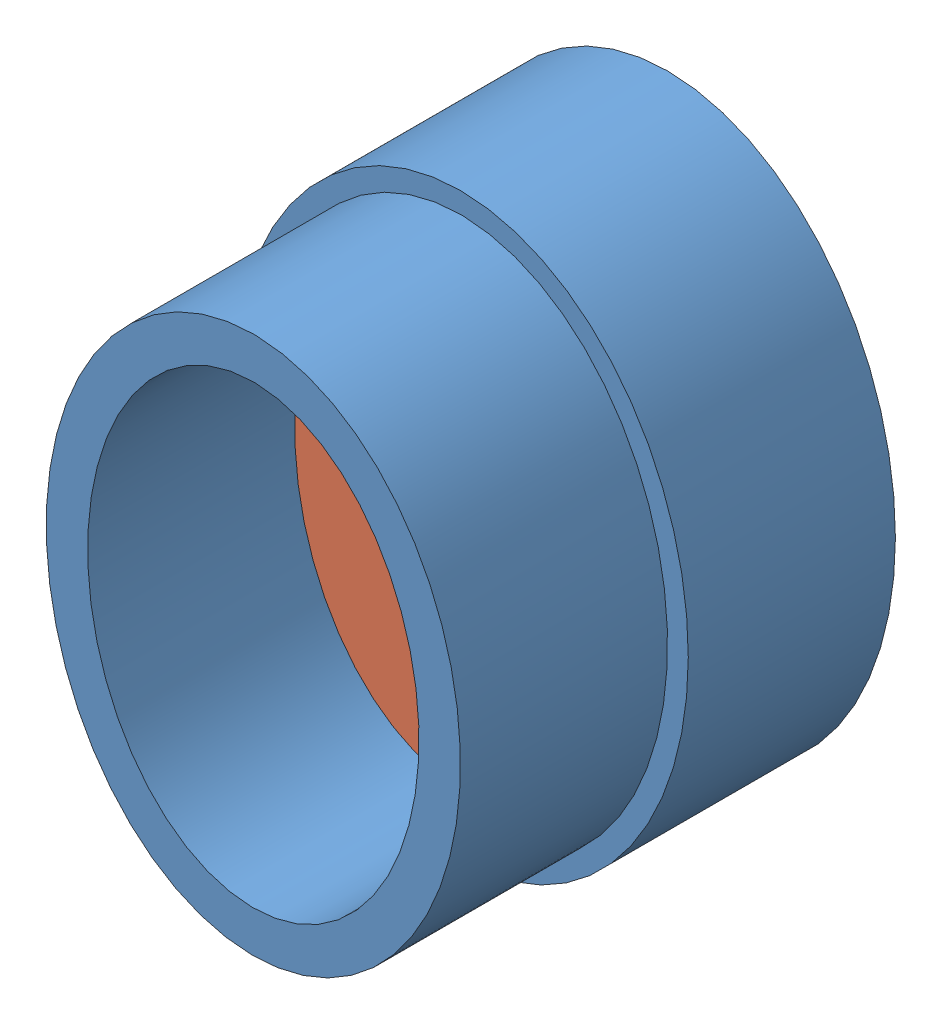
SolidWorks assembly ojo izq, configuration Predeterminado. Lengths in mm.
Overall size (24.18 30.22 22.23).
2 component instances, 2 part files, 1 mates.
Components (placement in the parent):
- ojo-1: ojo [Predeterminado] at (-0.1179 1.8575 28) size (24.18 30.22 20)
- pupila2-2: pupila2 [Predeterminado] at (-0.1344 1.8621 38) x (-1 0 0) z (0 0 -1) size (18 24 12.23)
Mates (geometry in assembly coordinates):
- Coincidente1: coincident anti-aligned: plane of ojo-1 through (-0.1179 1.8575 30) normal (0 0 -1); plane of pupila2-2 through (-0.1344 1.8621 30) normal (0 0 1)
